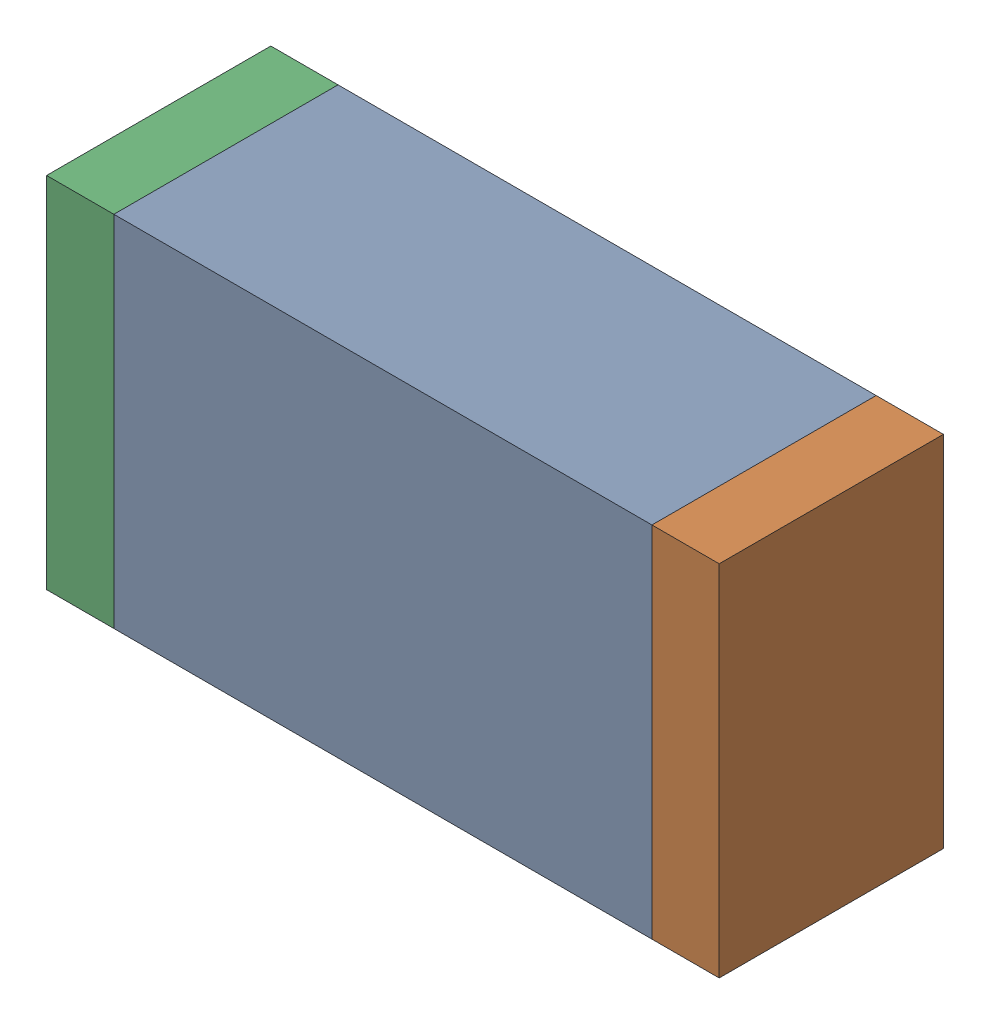
SolidWorks assembly L8, configuration Default. Lengths in mm.
Overall size (1.5 0.8 0.5).
6 component instances, 2 part files, 0 mates.
Components (placement in the parent):
- 836752368-1: 836752368 [Default] at (122.7 33.3 0) size (1.2 0.8 0.5)
  - Extruded-1: Extruded [Default] at origin size (1.2 0.8 0.5)
- 836752496-1: 836752496 [Default] at (123.375 33.3 0) size (0.15 0.8 0.5)
  - Extruded_2-1: Extruded_2 [Default] at origin size (0.15 0.8 0.5)
- 836752496-2: 836752496 [Default] at (122.025 33.3 0) size (0.15 0.8 0.5)
  - Extruded_2-1: Extruded_2 [Default] at origin size (0.15 0.8 0.5)
